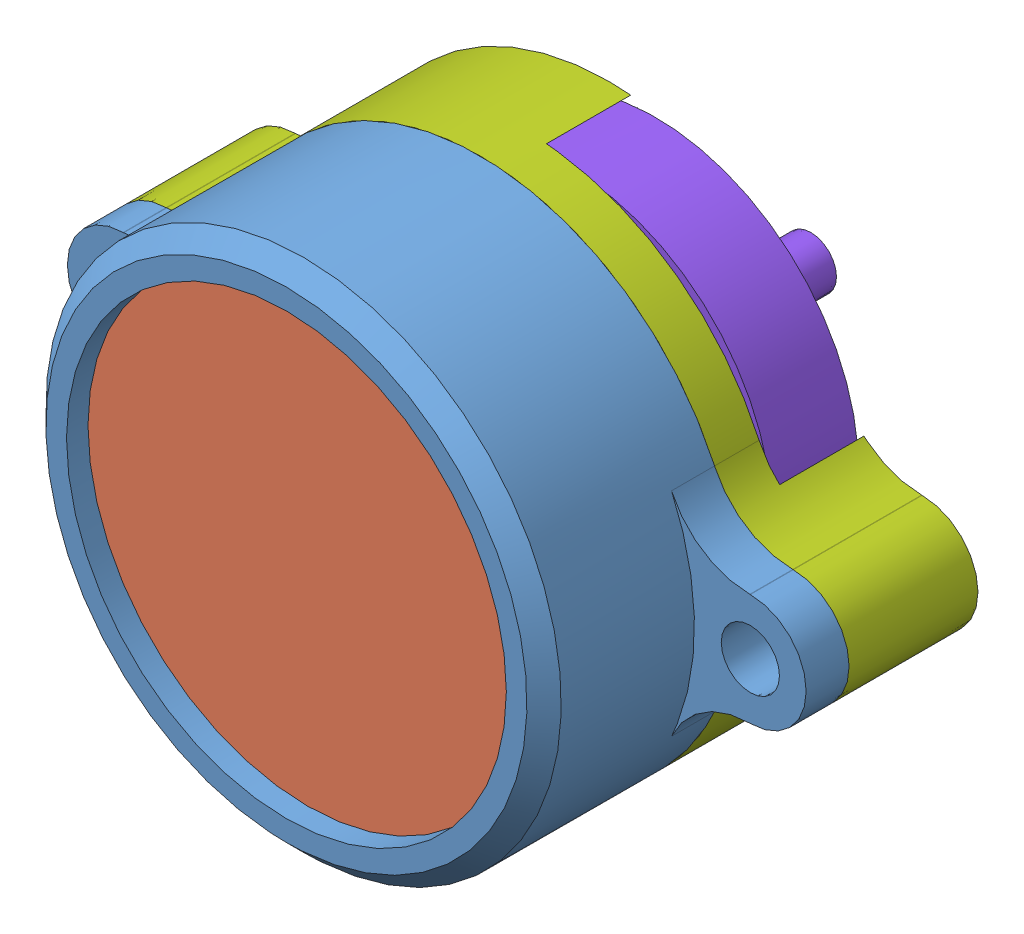
SolidWorks assembly Brake Pressure Indicator, configuration Default. Lengths in mm.
Overall size (54.61 48.34 28.38).
14 component instances, 11 part files, 38 mates.
Components (placement in the parent):
- 1.5 IN Case-1: 1.5 IN Case [Default] x (1 0 0) z (0 -1 0) size (54.61 14.29 38.1)
- 1.5 Indicator Glass-1: 1.5 Indicator Glass [Default] at (0 0 -1.5875) x (-1 0 0) z (0 0 -1) size (32.84 32.84 1.59)
- Brake Pressure Indicator Shroud-1: Brake Pressure Indicator Shroud [Default] at (0 0 -3.175) x (-1 0 0) z (0 0 -1) size (32.84 32.84 1.59)
- Brake Pressure Indicator Spacer-2: Brake Pressure Indicator Spacer [Default] at (0 0 -4.7625) x (-0.983256 0.18223 0) z (0 0 -1) size (32.84 32.84 4.76)
- Brake Pressure Indicator Needle-1: Brake Pressure Indicator Needle [Default] at (3.3056 3.3056 -6.0325) x (-0.707107 0.707107 0) z (0 0 1) size (2.38 17.46 1.59)
- Brake Pressure Indicator Bezel Face-2: Brake Pressure Indicator Bezel Face [Default] at (0 0 -11.1125) x (-0.707107 0.707107 0) z (0 0 1) size (32.84 32.84 1.59)
- Brake Pressure Indicator Rear Bezel Spacer-1: Brake Pressure Indicator Rear Bezel Spacer [Default] at (0 0 -11.1125) x (1 0 0) z (0 0 -1) size (54.61 38.1 12.7)
- VID29-02-1: VID29-02 [Default] at (3.3056 3.3056 -23.9825) x (-0.707107 0.707107 0) z (0.707107 0.707107 0) size (31.7 22.35 29.3)
- 93365A130_BRASS HEAT-SET INSERT FOR PLASTICS_6-32-3: 93365A130_BRASS HEAT-SET INSERT FOR PLASTICS_6-32 [93365A130] at (-23.1775 0 -14.2875) x (1 0 0) z (0 -1 0) size (5.56 4.29 5.56)
- 93365A130_BRASS HEAT-SET INSERT FOR PLASTICS_6-32-4: 93365A130_BRASS HEAT-SET INSERT FOR PLASTICS_6-32 [93365A130] at (23.1775 0 -14.2875) x (0.987351 0.158553 0) z (0.158553 -0.987351 0) size (5.56 4.29 5.56)
- 93365A102 - INSERT, 0-80, BRASS, FOR PLASTICS-1: 93365A102 - INSERT, 0-80, BRASS, FOR PLASTICS [Default] at (-6.2403 12.8516 -17.5825) x (1 0 0) z (0 1 0) size (3.58 3.01 3.58)
- 93365A102 - INSERT, 0-80, BRASS, FOR PLASTICS-2: 93365A102 - INSERT, 0-80, BRASS, FOR PLASTICS [Default] at (12.8516 -6.2403 -17.5825) x (1 0 0) z (0 1 0) size (3.58 3.01 3.58)
- 91772A064 - PHS, 0-80 x .4375, 18-8-1: 91772A064 - PHS, 0-80 x .4375, 18-8 [91772A064] at (12.8516 -6.2403 -13.17) x (-0.953265 0.302136 0) z (0 0 -1) size (2.95 2.95 12.24)
- 91772A064 - PHS, 0-80 x .4375, 18-8-2: 91772A064 - PHS, 0-80 x .4375, 18-8 [91772A064] at (-6.2403 12.8516 -13.17) x (-0.997396 0.072119 0) z (0 0 -1) size (2.95 2.95 12.24)
Mates (geometry in assembly coordinates):
- Coincident1: coincident aligned: plane of 1.5 IN Case-1 through (0 0 0) normal (1 0 0); plane of assembly through (0 0 0) normal (1 0 0)
- Coincident2: coincident aligned: plane of 1.5 IN Case-1 through (0 0 0) normal (0 0 1); plane of assembly through (0 0 0) normal (0 0 1)
- Coincident3: coincident anti-aligned: plane of 1.5 IN Case-1 through (0 0 0) normal (0 -1 0); plane of assembly through (0 0 0) normal (0 1 0)
- InPlace1: in place: plane of 1.5 IN Case-1 through (0 0 -1.5875) normal (0 0 -1); plane of 1.5 Indicator Glass-1 through (0 0 -1.5875) normal (0 0 -1); moOrthogonalPlaneRef_w of 1.5 IN Case-1 through (0 0 -1.5875) normal (0 0 -1); unknown of 1.5 Indicator Glass-1; plane of 1.5 IN Case-1 through (0 0 -1.5875) normal (0 0 -1); plane of 1.5 Indicator Glass-1 through (0 0 -1.5875) normal (-1 0 0); plane of 1.5 IN Case-1 through (0 0 -1.5875) normal (0 0 -1); unknown of 1.5 Indicator Glass-1
- Coincident4: coincident aligned: plane of 1.5 IN Case-1; plane of 1.5 Indicator Glass-1
- Coincident5: coincident aligned: moOrthogonalPlaneRef_w of 1.5 IN Case-1 through (0 0 -1.5875) normal (0 1 0); plane of 1.5 Indicator Glass-1 through (0 0 -1.5875) normal (0 1 0)
- Coincident6: coincident anti-aligned: moOrthogonalPlaneRef_w of 1.5 IN Case-1 through (0 0 -1.5875) normal (1 0 0); plane of 1.5 Indicator Glass-1 through (0 0 -1.5875) normal (-1 0 0)
- Concentric1: concentric anti-aligned: cylinder of 1.5 IN Case-1 through (0 0 -1.5875) axis (0 0 1) radius 19.05; cylinder of Brake Pressure Indicator Bezel Face-2 through (0 0 -9.525) axis (0 0 -1) radius 16.4211
- Angle1: planar angle = 0.785398 rad anti-aligned: plane of Brake Pressure Indicator Bezel Face-2 through (0 0 -11.1125) normal (-0.707107 0.707107 0); plane of assembly through (0 0 0) normal (1 0 0)
- Coincident14: coincident anti-aligned: plane of Brake Pressure Indicator Spacer-2 through (0 0 -9.525) normal (0 0 -1); plane of Brake Pressure Indicator Bezel Face-2 through (0 0 -9.525) normal (0 0 1)
- Concentric63: concentric aligned: cylinder of 1.5 IN Case-1 through (0 0 -64.994) axis (0 0 1) radius 16.6687; cylinder of Brake Pressure Indicator Rear Bezel Spacer-1 through (0 0 -17.4625) axis (0 0 1) radius 7.9375
- Concentric64: concentric aligned: cylinder of 1.5 IN Case-1 through (-23.1775 0 -14.2875) axis (0 0 1) radius 4.1275; cylinder of Brake Pressure Indicator Rear Bezel Spacer-1 through (-23.1775 0 -23.8125) axis (0 0 1) radius 4.1275
- Coincident109: coincident anti-aligned: plane of 1.5 IN Case-1 through (0 0 -14.2875) normal (0 0 -1); plane of Brake Pressure Indicator Rear Bezel Spacer-1 through (23.1775 0 -14.2875) normal (0 0 1)
- Concentric67: concentric anti-aligned: cone of Brake Pressure Indicator Rear Bezel Spacer-1 through (-23.1775 0 -14.2875) axis (0 0 -1); cylinder of 93365A130_BRASS HEAT-SET INSERT FOR PLASTICS_6-32-3 through (-23.1775 0 -14.2875) axis (0 0 1) radius 2.5273
- Coincident113: coincident aligned: plane of Brake Pressure Indicator Rear Bezel Spacer-1 through (23.1775 0 -14.2875) normal (0 0 1); plane of 93365A130_BRASS HEAT-SET INSERT FOR PLASTICS_6-32-3 through (-23.1775 0 -14.2875) normal (0 0 1)
- Coincident114: coincident aligned: plane of Brake Pressure Indicator Rear Bezel Spacer-1 through (23.1775 0 -14.2875) normal (0 0 1); plane of 93365A130_BRASS HEAT-SET INSERT FOR PLASTICS_6-32-4 through (23.1775 0 -14.2875) normal (0 0 1)
- Concentric68: concentric anti-aligned: cone of Brake Pressure Indicator Rear Bezel Spacer-1 through (23.1775 0 -14.2875) axis (0 0 -1); cylinder of 93365A130_BRASS HEAT-SET INSERT FOR PLASTICS_6-32-4 through (23.1775 0 -14.2875) axis (0 0 1) radius 2.5273
- Concentric69: concentric aligned: cylinder of 1.5 IN Case-1 through (0 0 -64.994) axis (0 0 1) radius 16.6687; cylinder of Brake Pressure Indicator Spacer-2 through (0 0 -9.525) axis (0 0 1) radius 15.9131
- InPlace2: in place: plane of 1.5 Indicator Glass-1 through (0 0 -3.175) normal (0 0 -1); plane of Brake Pressure Indicator Shroud-1 through (0 0 -3.175) normal (0 0 -1); plane of 1.5 Indicator Glass-1 through (0 0 -3.175) normal (0 0 -1); plane of Brake Pressure Indicator Shroud-1 through (0 0 -3.175) normal (0 1 0); plane of 1.5 Indicator Glass-1 through (0 0 -3.175) normal (0 0 -1); plane of Brake Pressure Indicator Shroud-1 through (0 0 -3.175) normal (-1 0 0); plane of 1.5 Indicator Glass-1 through (0 0 -3.175) normal (0 0 -1); unknown of Brake Pressure Indicator Shroud-1
- Coincident115: coincident aligned: plane of 1.5 Indicator Glass-1; plane of Brake Pressure Indicator Shroud-1
- Coincident116: coincident aligned: moOrthogonalPlaneRef_w of 1.5 Indicator Glass-1 through (0 0 -3.175) normal (0 1 0); plane of Brake Pressure Indicator Shroud-1 through (0 0 -3.175) normal (0 1 0)
- Coincident117: coincident anti-aligned: moOrthogonalPlaneRef_w of 1.5 Indicator Glass-1 through (0 0 -3.175) normal (1 0 0); plane of Brake Pressure Indicator Shroud-1 through (0 0 -3.175) normal (-1 0 0)
- Coincident118: coincident anti-aligned: plane of Brake Pressure Indicator Spacer-2 through (0 0 -4.7625) normal (0 0 1); plane of Brake Pressure Indicator Shroud-1 through (0 0 -4.7625) normal (0 0 -1)
- Concentric70: concentric anti-aligned: cylinder of Brake Pressure Indicator Bezel Face-2 through (7.5483 7.5483 -11.1125) axis (0 0 1) radius 0.7937; cylinder of VID29-02-1 through (7.5483 7.5483 -17.5825) axis (0 0 -1) radius 0.5
- Distance12: distance = 1.27 mm anti-aligned: plane of VID29-02-1 through (7.5483 7.5483 -6.0325) normal (0 0 1); plane of Brake Pressure Indicator Shroud-1 through (0 0 -4.7625) normal (0 0 -1)
- Coincident119: coincident aligned: plane of Brake Pressure Indicator Bezel Face-2 through (0 0 -11.1125) normal (-0.707107 0.707107 0); plane of VID29-02-1 through (3.3056 3.3056 -23.9825) normal (-0.707107 0.707107 0)
- Concentric71: concentric aligned: cone of Brake Pressure Indicator Rear Bezel Spacer-1 through (-6.2403 12.8516 -17.5825) axis (0 0 1); cone of 93365A102 - INSERT, 0-80, BRASS, FOR PLASTICS-1 through (-6.2403 12.8516 -16.4725) axis (0 0 1)
- Coincident120: coincident aligned: plane of Brake Pressure Indicator Rear Bezel Spacer-1 through (3.3056 3.3056 -17.5825) normal (0 0 -1); plane of 93365A102 - INSERT, 0-80, BRASS, FOR PLASTICS-1 through (-8.031 12.8516 -17.5825) normal (0 0 -1)
- Concentric72: concentric aligned: cone of Brake Pressure Indicator Rear Bezel Spacer-1 through (12.8516 -6.2403 -17.5825) axis (0 0 1); cone of 93365A102 - INSERT, 0-80, BRASS, FOR PLASTICS-2 through (12.8516 -6.2403 -16.4725) axis (0 0 1)
- Coincident121: coincident aligned: plane of Brake Pressure Indicator Rear Bezel Spacer-1 through (3.3056 3.3056 -17.5825) normal (0 0 -1); plane of 93365A102 - INSERT, 0-80, BRASS, FOR PLASTICS-2 through (11.0609 -6.2403 -17.5825) normal (0 0 -1)
- Concentric73: concentric aligned: cylinder of VID29-02-1 through (12.8516 -6.2403 -24.2825) axis (0 0 -1) radius 0.925; circle of 91772A064 - PHS, 0-80 x .4375, 18-8-1
- Coincident122: coincident anti-aligned: plane of VID29-02-1 through (3.3056 3.3056 -24.2825) normal (0 0 -1); plane of 91772A064 - PHS, 0-80 x .4375, 18-8-1 through (12.8516 -6.2403 -24.2825) normal (0 0 1)
- Concentric74: concentric aligned: cylinder of Brake Pressure Indicator Rear Bezel Spacer-1 through (-6.2403 12.8516 -17.5825) axis (0 0 -1) radius 0.9271; circle of 91772A064 - PHS, 0-80 x .4375, 18-8-2
- Coincident123: coincident anti-aligned: plane of VID29-02-1 through (3.3056 3.3056 -24.2825) normal (0 0 -1); plane of 91772A064 - PHS, 0-80 x .4375, 18-8-2 through (-6.2403 12.8516 -24.2825) normal (0 0 1)
- InPlace3: in place: plane of VID29-02-1 through (7.5483 7.5483 -6.0325) normal (0 0 1); plane of ? through (0 0 -6.0325) normal (0 0 1); plane of VID29-02-1 through (7.5483 7.5483 -6.0325) normal (0 0 1); plane of ? through (0 0 -6.0325) normal (0 1 0); plane of VID29-02-1 through (7.5483 7.5483 -6.0325) normal (0 0 1); plane of ? through (0 0 -6.0325) normal (1 0 0); plane of VID29-02-1 through (7.5483 7.5483 -6.0325) normal (0 0 1); unknown of Brake Pressure Indicator Needle-1
- Coincident124: coincident aligned: plane of VID29-02-1; plane of Brake Pressure Indicator Needle-1
- Coincident125: coincident aligned: moOrthogonalPlaneRef_w of VID29-02-1 through (3.3056 3.3056 -6.0325) normal (-0.707107 -0.707107 0); plane of Brake Pressure Indicator Needle-1 through (3.3056 3.3056 -6.0325) normal (-0.707107 -0.707107 0)
- Coincident126: coincident anti-aligned: moOrthogonalPlaneRef_w of VID29-02-1 through (3.3056 3.3056 -6.0325) normal (0.707107 -0.707107 0); plane of Brake Pressure Indicator Needle-1 through (3.3056 3.3056 -6.0325) normal (-0.707107 0.707107 0)
